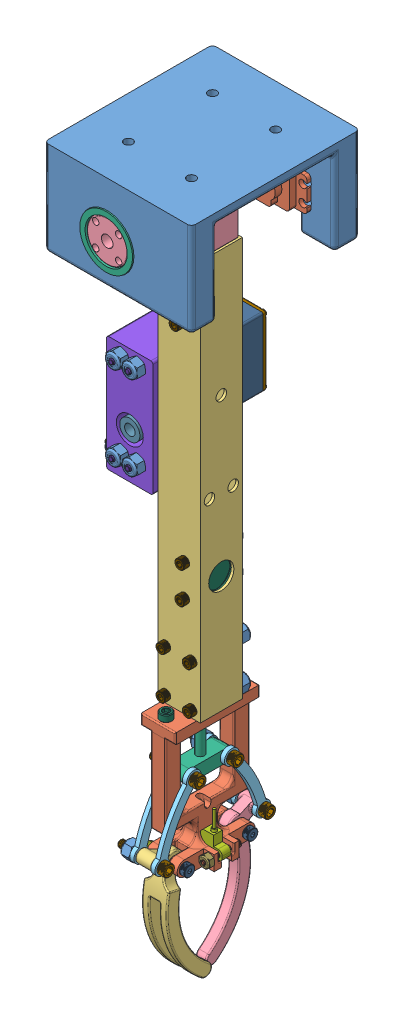
SolidWorks assembly Piston Linkage Gripper with Arm, configuration Default. Lengths in mm.
Overall size (100.54 441.41 113.6).
86 component instances, 36 part files, 3 mates.
Components (placement in the parent):
- MS-SA-0013d-03-Gripper Arm-1: MS-SA-0013d-03-Gripper Arm [Default] at (9.7903 164.2827 287.4567) size (100.54 301.68 113.6) (flexible)
  - MS-P-0057-03-Gripper Arm Mount-1: MS-P-0057-03-Gripper Arm Mount [Default] at (-52.2477 40.78 53.3156) x (0 0 1) z (0 1 0) size (101.6 88.9 57.15)
  - MS-SA-0013b-03-Shoulder Servo Mount Assembly-1: MS-SA-0013b-03-Shoulder Servo Mount Assembly [Default] at (2.0387 62.0863 -50.1865) x (0 1 0) z (1 0 0) size (20 43.5 53.2)
    - MS-C-0032-Gripper Shoulder Servo-1: MS-C-0032-Gripper Shoulder Servo [Default] at (-48.0063 17.0406 -6.2663) x (0 0 -1) z (1 0 0) size (53.2 43.5 20)
  - MS-P-0054-03-Box Tubing-1: MS-P-0054-03-Box Tubing [Default] at (-14.2277 -11.955 -2.8819) x (0 0 -1) z (0 -1 0) size (25.4 25.4 241.3)
  - MS-P-0058-03-Shoulder L Joint-1: MS-P-0058-03-Shoulder L Joint [Default] at (-14.2277 14.08 -2.1834) x (0 0 -1) z (0 -1 0) size (66.61 26.61 88.65)
  - 525130.step-1: 525130.step [Default] at (-14.2277 14.08 -19.6459) x (1 0 0) z (0 -1 0) size (25.39 6.35 25.39)
  - MS-C-0028-03-Servo Arm Bushing-1: MS-C-0028-03-Servo Arm Bushing [2934T25] at (-14.2277 14.08 34.9006) x (1 0 0) z (0 -1 0) size (38.1 19.05 38.1)
  - 97171A170_ HEAT-SET INSERT FOR PLASTIC_V3-1: 97171A170_ HEAT-SET INSERT FOR PLASTIC_V3 [97171A170] at (19.7723 19.08 -40.131) x (-0.536856 0.843674 0) z (-0.843674 -0.536856 0) size (7.14 9.57 7.14)
  - 97171A170_ HEAT-SET INSERT FOR PLASTIC_V3-2: 97171A170_ HEAT-SET INSERT FOR PLASTIC_V3 [97171A170] at (19.7723 9.08 -40.131) x (-0.383049 0.923728 0) z (-0.923728 -0.383049 0) size (7.14 9.57 7.14)
  - 97171A170_ HEAT-SET INSERT FOR PLASTIC_V3-3: 97171A170_ HEAT-SET INSERT FOR PLASTIC_V3 [97171A170] at (-28.2277 19.08 -40.131) x (-0.940007 -0.341154 0) z (0.341154 -0.940007 0) size (7.14 9.57 7.14)
  - 97171A170_ HEAT-SET INSERT FOR PLASTIC_V3-4: 97171A170_ HEAT-SET INSERT FOR PLASTIC_V3 [97171A170] at (-28.2277 9.08 -40.131) x (-0.231744 0.972777 0) z (-0.972777 -0.231744 0) size (7.14 9.57 7.14)
  - MS-SA-0013a-03-Hand Servo Mount Assembly-1: MS-SA-0013a-03-Hand Servo Mount Assembly [Default] at (-74.8369 -56.8346 16.8315) x (0 0 -1) z (0 -1 0) size (72.39 31.33 69.75)
    - MS-P-0055-03 Hand Servo Mount-1: MS-P-0055-03 Hand Servo Mount [Default] at (12.5808 33.9393 61.1705) size (41.76 27.94 69.75)
    - 11886-1: 11886 [Default] at (71.9223 31.717 49.4945) x (0 1 0) z (0 0 1) size (21 45.43 55.5)
      - 11886_bottom-1: 11886_bottom [Default] at (2.2223 -4.2785 0.9275) size (21 2.43 41.5)
      - 11886_middle-1: 11886_middle [Default] at (2.2223 -1.8785 0.9275) size (21 25.7 42.9)
      - 11886_upper-1: 11886_upper [Default] at (6.1473 23.8215 -5.3225) size (21 8.72 55.5)
      - 11886_top-1: 11886_top [Default] at (2.2223 32.5215 0.7275) size (20 8.6 36.5)
    - MS-C-0027-Servo Horn-1: MS-C-0027-Servo Horn [Default] at (34.0008 33.9393 61.172) x (0 0.962595 -0.270945) z (0 0.270945 0.962595) size (25.39 6.35 25.39)
    - MS-P-0060-03-Hand Servo Pulley-1: MS-P-0060-03-Hand Servo Pulley [Default] at (22.8883 33.9393 61.172) x (0 0.270945 0.962595) z (0 -0.962595 0.270945) size (25.4 23.81 25.4)
  - MS-P-0047-Gripper Electromagnet Mount Inside Arm-1: MS-P-0047-Gripper Electromagnet Mount Inside Arm [Default] at (-15.8152 -182.77 -2.8819) x (0 -1 0) z (0 0 1) size (31.75 12.7 22.1)
  - 92196A167_18-8 STAINLESS STEEL SOCKET HEAD SCREW-1: 92196A167_18-8 STAINLESS STEEL SOCKET HEAD SCREW [92196A167] at (-63.4402 -138.955 4.2619) x (0 -0.178911 -0.983865) z (-1 0 0) size (5.73 5.73 42.21)
  - 92196A167_18-8 STAINLESS STEEL SOCKET HEAD SCREW-2: 92196A167_18-8 STAINLESS STEEL SOCKET HEAD SCREW [92196A167] at (-63.4402 -138.955 -10.0256) x (0 0.009709 -0.999953) z (-1 0 0) size (5.73 5.73 42.21)
  - 92196A167_18-8 STAINLESS STEEL SOCKET HEAD SCREW-3: 92196A167_18-8 STAINLESS STEEL SOCKET HEAD SCREW [92196A167] at (-63.4402 -88.155 -2.8819) x (0 0.225044 -0.974349) z (-1 0 0) size (5.73 5.73 42.21)
  - 92196A169_18-8 STAINLESS STEEL SOCKET HEAD SCREW-7: 92196A169_18-8 STAINLESS STEEL SOCKET HEAD SCREW [92196A169] at (-35.8977 -81.9066 19.5306) x (-0.225494 0.974245 0) z (0 0 1) size (5.73 5.73 54.99)
  - 92196A169_18-8 STAINLESS STEEL SOCKET HEAD SCREW-8: 92196A169_18-8 STAINLESS STEEL SOCKET HEAD SCREW [92196A169] at (-45.8976 -81.9066 19.5306) x (0.191778 -0.981438 0) z (0 0 1) size (5.73 5.73 54.99)
  - 92196A169_18-8 STAINLESS STEEL SOCKET HEAD SCREW-9: 92196A169_18-8 STAINLESS STEEL SOCKET HEAD SCREW [92196A169] at (-35.8977 -132.605 19.5306) x (0.056433 -0.998406 0) z (0 0 1) size (5.73 5.73 54.99)
  - 92196A169_18-8 STAINLESS STEEL SOCKET HEAD SCREW-10: 92196A169_18-8 STAINLESS STEEL SOCKET HEAD SCREW [92196A169] at (-45.8976 -132.605 19.5306) x (-0.049736 -0.998762 0) z (0 0 1) size (5.73 5.73 54.99)
  - 92196A166_18-8 STAINLESS STEEL SOCKET HEAD SCREW-13: 92196A166_18-8 STAINLESS STEEL SOCKET HEAD SCREW [92196A166] at (-10.7352 -173.245 -21.9319) x (0.59674 0.802434 0) z (0 0 -1) size (5.73 5.73 35.83)
  - 92196A166_18-8 STAINLESS STEEL SOCKET HEAD SCREW-15: 92196A166_18-8 STAINLESS STEEL SOCKET HEAD SCREW [92196A166] at (-10.7352 -192.295 -21.9319) x (0.615426 0.788195 0) z (0 0 -1) size (5.73 5.73 35.83)
  - 90631A009_Low-Strength Steel Nylon-Insert Locknut-1: 90631A009_Low-Strength Steel Nylon-Insert Locknut [90631A009] at (-54.8677 -88.155 -2.8819) x (0 0.837169 -0.546944) z (0 0.546944 0.837169) size (8.73 6.09 10.08)
  - 90631A009_Low-Strength Steel Nylon-Insert Locknut-2: 90631A009_Low-Strength Steel Nylon-Insert Locknut [90631A009] at (-54.8677 -138.955 4.2619) x (0 0.925243 -0.379375) z (0 0.379375 0.925243) size (8.73 6.09 10.08)
  - 90631A009_Low-Strength Steel Nylon-Insert Locknut-3: 90631A009_Low-Strength Steel Nylon-Insert Locknut [90631A009] at (-54.8677 -138.955 -10.0256) x (0 0.985271 -0.170998) z (0 0.170998 0.985271) size (8.73 6.09 10.08)
  - 90631A009_Low-Strength Steel Nylon-Insert Locknut-5: 90631A009_Low-Strength Steel Nylon-Insert Locknut [90631A009] at (-35.8977 -132.605 12.9931) x (-0.987107 -0.16006 0) z (-0.16006 0.987107 0) size (8.73 6.09 10.08)
  - 90631A009_Low-Strength Steel Nylon-Insert Locknut-7: 90631A009_Low-Strength Steel Nylon-Insert Locknut [90631A009] at (-45.8976 -132.605 12.9931) x (-0.994509 -0.104651 0) z (-0.104651 0.994509 0) size (8.73 6.09 10.08)
  - 90631A009_Low-Strength Steel Nylon-Insert Locknut-9: 90631A009_Low-Strength Steel Nylon-Insert Locknut [90631A009] at (-35.8977 -81.9066 12.9931) x (-0.993677 -0.112278 0) z (-0.112278 0.993677 0) size (8.73 6.09 10.08)
  - 90631A009_Low-Strength Steel Nylon-Insert Locknut-11: 90631A009_Low-Strength Steel Nylon-Insert Locknut [90631A009] at (-45.8976 -81.9066 12.9931) x (-0.593284 0.804993 0) z (0.804993 0.593284 0) size (8.73 6.09 10.08)
  - 90631A009_Low-Strength Steel Nylon-Insert Locknut-13: 90631A009_Low-Strength Steel Nylon-Insert Locknut [90631A009] at (-10.7352 -192.295 -15.5819) x (0.013782 -0.999905 0) z (0.999905 0.013782 0) size (8.73 6.09 10.08)
  - 90631A009_Low-Strength Steel Nylon-Insert Locknut-15: 90631A009_Low-Strength Steel Nylon-Insert Locknut [90631A009] at (-10.7352 -173.245 -15.5819) x (0.187204 -0.982321 0) z (0.982321 0.187204 0) size (8.73 6.09 10.08)
  - 92196A166_18-8 STAINLESS STEEL SOCKET HEAD SCREW-17: 92196A166_18-8 STAINLESS STEEL SOCKET HEAD SCREW [92196A166] at (-6.2902 -223.029 -21.9319) x (-0.902884 0.429884 0) z (0 0 -1) size (5.73 5.73 35.83)
  - 92196A166_18-8 STAINLESS STEEL SOCKET HEAD SCREW-18: 92196A166_18-8 STAINLESS STEEL SOCKET HEAD SCREW [92196A166] at (-6.2902 -248.429 -21.9319) x (0.224376 0.974503 0) z (0 0 -1) size (5.73 5.73 35.83)
  - 92196A166_18-8 STAINLESS STEEL SOCKET HEAD SCREW-19: 92196A166_18-8 STAINLESS STEEL SOCKET HEAD SCREW [92196A166] at (-22.1652 -223.029 -21.9319) x (0.278925 0.960313 0) z (0 0 -1) size (5.73 5.73 35.83)
  - 92196A166_18-8 STAINLESS STEEL SOCKET HEAD SCREW-20: 92196A166_18-8 STAINLESS STEEL SOCKET HEAD SCREW [92196A166] at (-22.1652 -248.429 -21.9319) x (0.226233 0.974073 0) z (0 0 -1) size (5.73 5.73 35.83)
  - 92196A166_18-8 STAINLESS STEEL SOCKET HEAD SCREW-21: 92196A166_18-8 STAINLESS STEEL SOCKET HEAD SCREW [92196A166] at (-14.2277 -24.655 -21.9319) x (0.216747 0.976228 0) z (0 0 -1) size (5.73 5.73 35.83)
  - 92196A166_18-8 STAINLESS STEEL SOCKET HEAD SCREW-22: 92196A166_18-8 STAINLESS STEEL SOCKET HEAD SCREW [92196A166] at (-14.2277 -50.055 -21.9319) x (0.256336 0.966588 0) z (0 0 -1) size (5.73 5.73 35.83)
  - 90631A009_Low-Strength Steel Nylon-Insert Locknut-16: 90631A009_Low-Strength Steel Nylon-Insert Locknut [90631A009] at (-6.2902 -223.029 -15.5819) x (-0.973129 -0.230259 0) z (0.230259 -0.973129 0) size (8.73 6.09 10.08)
  - 90631A009_Low-Strength Steel Nylon-Insert Locknut-17: 90631A009_Low-Strength Steel Nylon-Insert Locknut [90631A009] at (-6.2902 -248.429 -15.5819) x (0.296175 -0.955134 0) z (0.955134 0.296175 0) size (8.73 6.09 10.08)
  - 90631A009_Low-Strength Steel Nylon-Insert Locknut-18: 90631A009_Low-Strength Steel Nylon-Insert Locknut [90631A009] at (-22.1652 -223.029 -15.5819) x (0.383916 -0.923368 0) z (0.923368 0.383916 0) size (8.73 6.09 10.08)
  - 90631A009_Low-Strength Steel Nylon-Insert Locknut-19: 90631A009_Low-Strength Steel Nylon-Insert Locknut [90631A009] at (-22.1652 -248.429 -15.5819) x (0.433613 -0.901099 0) z (0.901099 0.433613 0) size (8.73 6.09 10.08)
  - 90631A009_Low-Strength Steel Nylon-Insert Locknut-20: 90631A009_Low-Strength Steel Nylon-Insert Locknut [90631A009] at (-14.2277 -50.055 -15.5819) x (0.442359 -0.896838 0) z (0.896838 0.442359 0) size (8.73 6.09 10.08)
  - 90631A009_Low-Strength Steel Nylon-Insert Locknut-21: 90631A009_Low-Strength Steel Nylon-Insert Locknut [90631A009] at (-14.2277 -24.655 -15.5819) x (-0.623475 -0.781844 0) z (0.781844 -0.623475 0) size (8.73 6.09 10.08)
- Piston Linkage Gripper-1: Piston Linkage Gripper [Default] at (52.3566 -117.8357 387.6476) x (0 -1 0) z (0 0 -1) size (188.74 36 110.7) (flexible)
  - Base-1: Base [Default] at (45.4317 56.7939 103.0728) size (113.67 26.29 50.8)
  - Two Finger Claw-1: Two Finger Claw [Default] at (27.8159 56.7939 91.2746) x (0.380673 0 0.92471) z (-0.92471 0 0.380673) size (57.48 15.24 61.26)
  - One Finger Claw-1: One Finger Claw [Default] at (27.8159 56.7939 114.871) x (0.380673 0 -0.92471) z (0.92471 0 0.380673) size (57.48 10.16 60.79)
  - Part2^Piston Linkage Gripper-1: Part2^Piston Linkage Gripper [Default] at origin (virtual)
  - Linkage_Curved-6: Linkage_Curved [Default] at (51.9548 51.7139 108.4814) x (0.990314 0 0.138849) z (0.138849 0 -0.990314) size (47.77 2.54 22.73)
  - Piston-1: Piston [Default] at (50.56 56.7939 103.0728) size (83.82 10.16 30.48)
  - MS-C-0034-Gripper-Limit-Switch-1: MS-C-0034-Gripper-Limit-Switch [Default] at (44.7651 56.7939 105.7228) x (0 -1 0) z (0 0 1) size (18.87 29.8 8.3)
    - D2HW_C262M_BASE-1: D2HW_C262M_BASE [Default] at origin size (18.5 26.81 8.3)
    - D2HW_C262M_ACTUATOR-1: D2HW_C262M_ACTUATOR [Default] at (10 3 -2.65) size (13.32 6.3 3.4)
  - 92196A199_18-8 Stainless Steel Socket Head Screw-1: 92196A199_18-8 Stainless Steel Socket Head Screw [92196A199] at (3.4347 59.7911 114.5028) x (-0.81884 0 0.574022) z (0 -1 0) size (6.85 6.85 30.12)
  - 92196A199_18-8 Stainless Steel Socket Head Screw-3: 92196A199_18-8 Stainless Steel Socket Head Screw [92196A199] at (3.4347 59.7911 91.6428) x (-0.695991 0 0.718051) z (0 -1 0) size (6.85 6.85 30.12)
  - 92196A199_18-8 Stainless Steel Socket Head Screw-6: 92196A199_18-8 Stainless Steel Socket Head Screw [92196A199] at (40.0197 59.7911 133.6119) x (-0.524834 0 0.851205) z (0 -1 0) size (6.85 6.85 30.12)
  - 92196A199_18-8 Stainless Steel Socket Head Screw-8: 92196A199_18-8 Stainless Steel Socket Head Screw [92196A199] at (40.0197 59.7911 72.5336) x (-0.310659 0 0.950521) z (0 -1 0) size (6.85 6.85 30.12)
  - 90631A009_Low-Strength Steel Nylon-Insert Locknut-1: 90631A009_Low-Strength Steel Nylon-Insert Locknut [90631A009] at (40.0197 64.4139 133.6119) x (-0.956354 0 0.292211) z (-0.292211 0 -0.956354) size (8.73 6.09 10.08)
  - 90631A009_Low-Strength Steel Nylon-Insert Locknut-4: 90631A009_Low-Strength Steel Nylon-Insert Locknut [90631A009] at (3.4347 64.4139 114.5028) x (-0.884149 0 0.467204) z (-0.467204 0 -0.884149) size (8.73 6.09 10.08)
  - 90631A009_Low-Strength Steel Nylon-Insert Locknut-6: 90631A009_Low-Strength Steel Nylon-Insert Locknut [90631A009] at (3.4347 64.4139 91.6428) x (-0.762644 0 0.646818) z (-0.646818 0 -0.762644) size (8.73 6.09 10.08)
  - 90631A009_Low-Strength Steel Nylon-Insert Locknut-8: 90631A009_Low-Strength Steel Nylon-Insert Locknut [90631A009] at (40.0197 64.4139 72.5336) x (-0.589757 0 0.807581) z (-0.807581 0 -0.589757) size (8.73 6.09 10.08)
  - 91259A403_Alloy Steel Shoulder Screw_Claw Rotation-1: 91259A403_Alloy Steel Shoulder Screw_Claw Rotation [91259A403] at (45.4317 44.0939 122.1228) x (-0.81884 0 0.574022) z (0 -1 0) size (6.35 6.35 26.56)
  - 91259A403_Alloy Steel Shoulder Screw_Claw Rotation-2: 91259A403_Alloy Steel Shoulder Screw_Claw Rotation [91259A403] at (45.4317 44.0939 84.0228) x (-0.695991 0 0.718051) z (0 -1 0) size (6.35 6.35 26.56)
  - 92196A096_18-8 Stainless Steel Socket Head Screw-1: 92196A096_18-8 Stainless Steel Socket Head Screw [92196A096] at (44.7651 43.7939 102.2981) x (0.70429 -0.709913 0) z (0 0 1) size (4.08 4.08 21.93)
  - 91831A004_18-8 Stainless Steel Nylon-Insert Locknut-1: 91831A004_18-8 Stainless Steel Nylon-Insert Locknut [91831A004] at (44.7651 43.7939 95.5798) x (-0.777952 0.628324 0) z (-0.628324 -0.777952 0) size (6.35 3.65 7.33)
  - Linkage_Curved-8: Linkage_Curved [Default] at (51.9548 64.4139 108.4814) x (0.990314 0 0.138849) z (0.138849 0 -0.990314) size (47.77 2.54 22.73)
  - Linkage_Curved-9: Linkage_Curved [Default] at (17.2415 51.7139 115.7957) x (-0.679738 0 0.733455) z (0.733455 0 0.679738) size (47.77 2.54 22.73)
  - Linkage_Curved-10: Linkage_Curved [Default] at (51.9548 61.8739 97.6641) x (0.990314 0 -0.138849) z (0.138849 0 0.990314) size (47.77 2.54 22.73)
  - 6389K1_Light Duty Dry-Running Nylon Sleeve Bearing-1: 6389K1_Light Duty Dry-Running Nylon Sleeve Bearing [6389K1] at (45.4317 56.7939 122.1228) x (0.955856 0 0.293834) z (0 -1 0) size (6.35 6.35 6.35)
  - 6389K1_Light Duty Dry-Running Nylon Sleeve Bearing-2: 6389K1_Light Duty Dry-Running Nylon Sleeve Bearing [6389K1] at (45.4317 56.7939 84.0228) x (0.994104 0 0.108433) z (0 -1 0) size (6.35 6.35 6.35)
  - 97171A170_Brass Heat-Set Inserts for Plastic-1: 97171A170_Brass Heat-Set Inserts for Plastic [97171A170] at (-13.5979 56.7939 82.4353) x (0 -0.924225 -0.381849) z (0 0.381849 -0.924225) size (7.14 9.57 7.14)
  - 97171A170_Brass Heat-Set Inserts for Plastic-2: 97171A170_Brass Heat-Set Inserts for Plastic [97171A170] at (-13.5979 56.7939 123.7103) x (0 0.941565 -0.33683) z (0 0.33683 0.941565) size (7.14 9.57 7.14)
  - 91251A197_Black-Oxide Alloy Steel Socket Head Screw-1: 91251A197_Black-Oxide Alloy Steel Socket Head Screw [91251A197] at (-21.4211 56.7939 123.7103) x (0 -0.982169 -0.187998) z (-1 0 0) size (6.86 6.86 23.8)
  - 91251A197_Black-Oxide Alloy Steel Socket Head Screw-2: 91251A197_Black-Oxide Alloy Steel Socket Head Screw [91251A197] at (-21.4211 56.7939 82.4353) x (0 -0.995355 0.096273) z (-1 0 0) size (6.86 6.86 23.8)
  - 91831A005_18-8 Stainless Steel Nylon-Insert Locknut-1: 91831A005_18-8 Stainless Steel Nylon-Insert Locknut [91831A005] at (45.4317 66.3189 84.0228) x (0.037063 0 0.999313) z (-0.999313 0 0.037063) size (6.35 3.66 7.33)
  - 91831A005_18-8 Stainless Steel Nylon-Insert Locknut-3: 91831A005_18-8 Stainless Steel Nylon-Insert Locknut [91831A005] at (45.4317 66.3189 122.1228) x (0.224725 0 0.974422) z (-0.974422 0 0.224725) size (6.35 3.66 7.33)
  - MS-P-0066-03 PVC Pipe-1: MS-P-0066-03 PVC Pipe [Default] at (-295.7186 -300.2843 143.409) x (0 -1 0) z (0 0 -1) size (25.4 25.4 127) (hidden)
Mates (geometry in assembly coordinates):
- Width2: width anti-aligned: plane of MS-SA-0013d-03-Gripper Arm-1/MS-P-0054-03-Box Tubing-1 through (8.2626 -88.9724 271.8748) normal (0 0 -1); plane of Piston Linkage Gripper-1/Base-1 through (8.2626 -88.9724 297.2748) normal (0 0 1); plane of MS-SA-0013d-03-Gripper Arm-1/MS-P-0054-03-Box Tubing-1 through (-14.8514 -54.0474 294.9888) normal (0 0 1); plane of Piston Linkage Gripper-1/Base-1 through (-14.8514 -54.0474 274.1608) normal (0 0 -1)
- Width3: width aligned: plane of MS-SA-0013d-03-Gripper Arm-1/MS-P-0054-03-Box Tubing-1 through (-17.1374 -88.9724 297.2748) normal (-1 0 0); plane of Piston Linkage Gripper-1/Base-1 through (8.2626 -88.9724 297.2748) normal (1 0 0); plane of MS-SA-0013d-03-Gripper Arm-1/MS-P-0054-03-Box Tubing-1 through (-14.8514 -54.0474 294.9888) normal (-1 0 0); plane of Piston Linkage Gripper-1/Base-1 through (5.9766 -54.0474 294.9888) normal (1 0 0)
- Coincident2: coincident anti-aligned: plane of MS-SA-0013d-03-Gripper Arm-1/MS-P-0054-03-Box Tubing-1 through (-4.4374 -88.9724 284.5748) normal (0 -1 0); plane of Piston Linkage Gripper-1/Base-1 through (-13.9624 -88.9724 284.5748) normal (0 1 0)
